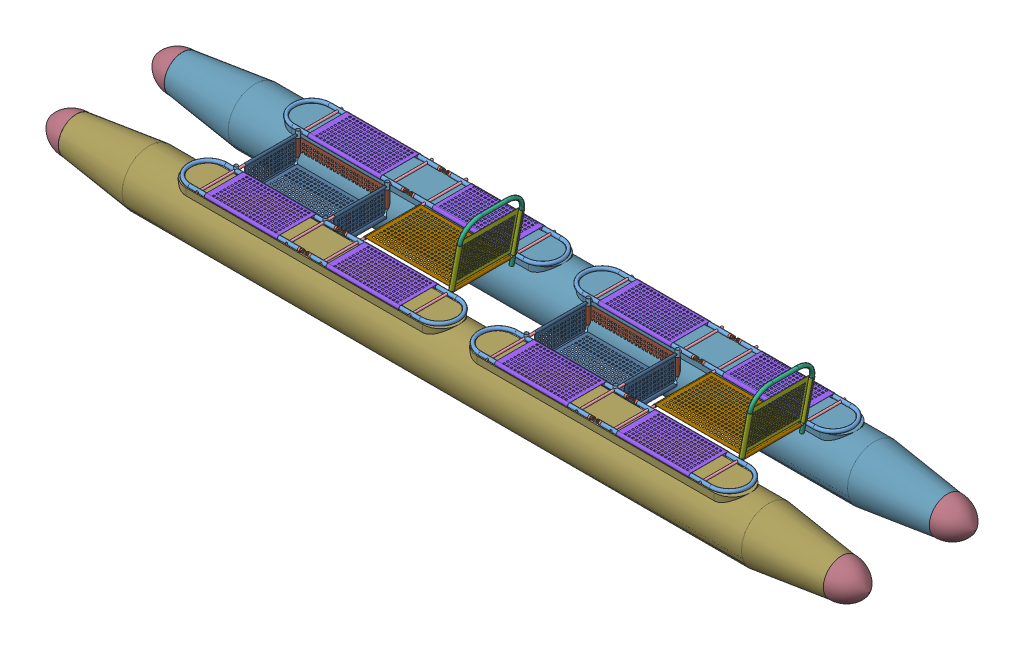
SolidWorks assembly VersionDobleV2, configuration Default. Lengths in mm.
Overall size (4504.33 666.94 886.13).
77 component instances, 14 part files, 8 mates.
Components (placement in the parent):
- FrameConTelas-1: FrameConTelas [Default] at (185.537 -150.3291 -304.6641) size (1488 506.65 807.68)
  - FrameOneSideNoAnim-1: FrameOneSideNoAnim [Default] at (577.8554 752.7862 1416.0585) size (1488 20 220)
    - F1-1: F1 [Default<As Welded>] at (120.0879 35.9229 252.3231) size (710 20 220)
    - H1-1: H1 [Default] at (120.0879 35.9229 252.3231) x (0 1 0) z (-1 0 0) size (20 20 40)
    - H2-1: H2 [Default] at (166.0879 29.9229 252.3231) x (1 0 0) z (0 1 0) size (36 12 6)
    - H1-2: H1 [Default] at (188.0879 35.9229 252.3231) x (0 1 0) z (1 0 0) size (20 20 40)
    - H2-2: H2 [Default] at (166.0879 29.9229 52.3231) x (1 0 0) z (0 1 0) size (36 12 6)
    - H1-4: H1 [Default] at (188.0879 35.9229 52.3231) x (0 1 0) z (1 0 0) size (20 20 40)
    - H1-6: H1 [Default] at (120.0879 35.9229 52.3231) x (0 1 0) z (-1 0 0) size (20 20 40)
    - F1-2: F1 [Default<As Welded>] at (188.0879 35.9229 52.3231) x (-1 0 0) z (0 0 -1) size (710 20 220)
  - FrameOneSideNoAnim-2: FrameOneSideNoAnim [Default] at (577.8554 752.7862 846.9204) size (1488 20 220)
    - F1-1: F1 [Default<As Welded>] at (120.0879 35.9229 252.3231) size (710 20 220)
    - H1-1: H1 [Default] at (120.0879 35.9229 252.3231) x (0 1 0) z (-1 0 0) size (20 20 40)
    - H2-1: H2 [Default] at (166.0879 29.9229 252.3231) x (1 0 0) z (0 1 0) size (36 12 6)
    - H1-2: H1 [Default] at (188.0879 35.9229 252.3231) x (0 1 0) z (1 0 0) size (20 20 40)
    - H2-2: H2 [Default] at (166.0879 29.9229 52.3231) x (1 0 0) z (0 1 0) size (36 12 6)
    - H1-4: H1 [Default] at (188.0879 35.9229 52.3231) x (0 1 0) z (1 0 0) size (20 20 40)
    - H1-6: H1 [Default] at (120.0879 35.9229 52.3231) x (0 1 0) z (-1 0 0) size (20 20 40)
    - F1-2: F1 [Default<As Welded>] at (188.0879 35.9229 52.3231) x (-1 0 0) z (0 0 -1) size (710 20 220)
  - F2-1: F2 [Default] at (147.9433 788.709 883.2223) x (0.974991 0.222245 0) z (0 0 1) size (12 12 800)
  - F2-2: F2 [Default] at (637.9433 788.709 877.7586) x (-0.420932 0.907092 0) z (0 0 1) size (12 12 800)
  - F2-3: F2 [Default] at (825.9433 788.709 876.0371) x (-0.580942 -0.813945 0) z (0 0 1) size (12 12 800)
  - F2-4: F2 [Default] at (1315.9433 788.709 883.7191) x (-0.357466 -0.933926 0) z (0 0 1) size (12 12 800)
  - F3-1: F3 [Default<As Welded>] at (147.9433 808.709 1464.7193) x (0 0 -1) z (1 0 0) size (400 170 20)
  - F3-2: F3 [Default<As Welded>] at (637.9433 808.709 1464.7193) x (0 0 -1) z (1 0 0) size (400 170 20)
  - F4-1: F4 [Default<As Welded>] at (1306.7067 739.5696 1111.2876) x (0 0 -1) z (0.982789 -0.184731 0) size (360 410 20)
  - T1-1: T1 [Default] at (1317.6609 797.8471 1111.2876) x (0 0 1) z (-0.982789 0.184731 0) size (363 240 23)
  - T2-1: T2 [Default] at (1270.4972 788.709 1099.2435) x (0 0 -1) z (0 1 0) size (223 400 23)
  - T2-2: T2 [Default] at (186.063 788.709 899.2435) x (0 0 1) z (0 1 0) size (223 400 23)
  - T2-3: T2 [Default] at (188.7365 788.709 1468.3816) x (0 0 1) z (0 1 0) size (223 400 23)
  - T2-4: T2 [Default] at (855.5815 788.709 1468.3816) x (0 0 1) z (0 1 0) size (223 400 23)
  - T3-1: T3 [Default] at (825.9433 788.709 1129.5821) size (505 15 310)
  - T4-1: T4 [Default] at (147.9433 648.709 1138.0439) size (512 158 280)
  - T5-1: T5 [Default] at (147.9433 684.6401 1124.7193) x (1 0 0) z (0 0 1) size (512 90 22)
  - T5-2: T5 [Default] at (637.9433 683.336 1464.7193) x (-1 0 0) z (0 0 -1) size (512 90 22)
- FrameConTelas-2: FrameConTelas [Default] at (-1407.9985 -150.3291 -304.6641) size (1488 506.65 807.68)
  - FrameOneSideNoAnim-1: FrameOneSideNoAnim [Default] at (577.8554 752.7862 1416.0585) size (1488 20 220)
    - F1-1: F1 [Default<As Welded>] at (120.0879 35.9229 252.3231) size (710 20 220)
    - H1-1: H1 [Default] at (120.0879 35.9229 252.3231) x (0 1 0) z (-1 0 0) size (20 20 40)
    - H2-1: H2 [Default] at (166.0879 29.9229 252.3231) x (1 0 0) z (0 1 0) size (36 12 6)
    - H1-2: H1 [Default] at (188.0879 35.9229 252.3231) x (0 1 0) z (1 0 0) size (20 20 40)
    - H2-2: H2 [Default] at (166.0879 29.9229 52.3231) x (1 0 0) z (0 1 0) size (36 12 6)
    - H1-4: H1 [Default] at (188.0879 35.9229 52.3231) x (0 1 0) z (1 0 0) size (20 20 40)
    - H1-6: H1 [Default] at (120.0879 35.9229 52.3231) x (0 1 0) z (-1 0 0) size (20 20 40)
    - F1-2: F1 [Default<As Welded>] at (188.0879 35.9229 52.3231) x (-1 0 0) z (0 0 -1) size (710 20 220)
  - FrameOneSideNoAnim-2: FrameOneSideNoAnim [Default] at (577.8554 752.7862 846.9204) size (1488 20 220)
    - F1-1: F1 [Default<As Welded>] at (120.0879 35.9229 252.3231) size (710 20 220)
    - H1-1: H1 [Default] at (120.0879 35.9229 252.3231) x (0 1 0) z (-1 0 0) size (20 20 40)
    - H2-1: H2 [Default] at (166.0879 29.9229 252.3231) x (1 0 0) z (0 1 0) size (36 12 6)
    - H1-2: H1 [Default] at (188.0879 35.9229 252.3231) x (0 1 0) z (1 0 0) size (20 20 40)
    - H2-2: H2 [Default] at (166.0879 29.9229 52.3231) x (1 0 0) z (0 1 0) size (36 12 6)
    - H1-4: H1 [Default] at (188.0879 35.9229 52.3231) x (0 1 0) z (1 0 0) size (20 20 40)
    - H1-6: H1 [Default] at (120.0879 35.9229 52.3231) x (0 1 0) z (-1 0 0) size (20 20 40)
    - F1-2: F1 [Default<As Welded>] at (188.0879 35.9229 52.3231) x (-1 0 0) z (0 0 -1) size (710 20 220)
  - F2-1: F2 [Default] at (147.9433 788.709 883.2223) x (0.974991 0.222245 0) z (0 0 1) size (12 12 800)
  - F2-2: F2 [Default] at (637.9433 788.709 877.7586) x (-0.420932 0.907092 0) z (0 0 1) size (12 12 800)
  - F2-3: F2 [Default] at (825.9433 788.709 876.0371) x (-0.580942 -0.813945 0) z (0 0 1) size (12 12 800)
  - F2-4: F2 [Default] at (1315.9433 788.709 883.7191) x (-0.357466 -0.933926 0) z (0 0 1) size (12 12 800)
  - F3-1: F3 [Default<As Welded>] at (147.9433 808.709 1464.7193) x (0 0 -1) z (1 0 0) size (400 170 20)
  - F3-2: F3 [Default<As Welded>] at (637.9433 808.709 1464.7193) x (0 0 -1) z (1 0 0) size (400 170 20)
  - F4-1: F4 [Default<As Welded>] at (1306.7067 739.5696 1111.2876) x (0 0 -1) z (0.982789 -0.184731 0) size (360 410 20)
  - T1-1: T1 [Default] at (1317.6609 797.8471 1111.2876) x (0 0 1) z (-0.982789 0.184731 0) size (363 240 23)
  - T2-1: T2 [Default] at (1270.4972 788.709 1099.2435) x (0 0 -1) z (0 1 0) size (223 400 23)
  - T2-2: T2 [Default] at (186.063 788.709 899.2435) x (0 0 1) z (0 1 0) size (223 400 23)
  - T2-3: T2 [Default] at (188.7365 788.709 1468.3816) x (0 0 1) z (0 1 0) size (223 400 23)
  - T2-4: T2 [Default] at (855.5815 788.709 1468.3816) x (0 0 1) z (0 1 0) size (223 400 23)
  - T3-1: T3 [Default] at (825.9433 788.709 1129.5821) size (505 15 310)
  - T4-1: T4 [Default] at (147.9433 648.709 1138.0439) size (512 158 280)
  - T5-1: T5 [Default] at (147.9433 684.6401 1124.7193) x (1 0 0) z (0 0 1) size (512 90 22)
  - T5-2: T5 [Default] at (637.9433 683.336 1464.7193) x (-1 0 0) z (0 0 -1) size (512 90 22)
- Ponton-1: Ponton [Default] at (3061.4153 -931.8418 263.4026) x (0 0 1) z (-1 0 0) size (300 300 4500)
  - P1-1: P1 [Default] at (1009.5571 1409.7476 1284.8904) size (300 300 4200)
  - P2-1: P2 [Default] at (1009.5571 1409.7476 884.8904) size (200 200 150)
  - P2-2: P2 [Default] at (1009.5571 1409.7476 5084.8904) x (-0.923728 -0.383049 0) z (0 0 -1) size (200 200 150)
- P1-R-2: P1-R [Default] at (1772.1996 477.0888 686.8298) x (0 0 1) z (-1 0 0) size (300 300 4200)
- P2-1: P2 [Default] at (2172.1996 477.0888 686.8298) x (0 0.924225 0.381849) z (-1 0 0) size (200 200 150)
- P2-2: P2 [Default] at (-2027.8004 477.0888 686.8298) x (0 -0.924225 -0.381849) z (1 0 0) size (200 200 150)
Mates (geometry in assembly coordinates):
- Coincident1: coincident anti-aligned: line of FrameConTelas-1/FrameOneSideNoAnim-1/F1-1 through (883.4803 638.38 1363.7175) axis (-1 0 0); line of FrameConTelas-2/FrameOneSideNoAnim-1/F1-2 through (-642.0552 638.38 1363.7175) axis (1 0 0)
- Coincident2: coincident anti-aligned: line of FrameConTelas-1/FrameOneSideNoAnim-2/F1-1 through (883.4803 638.38 594.5794) axis (-1 0 0); line of FrameConTelas-2/FrameOneSideNoAnim-2/F1-2 through (-642.0552 638.38 594.5794) axis (1 0 0)
- Parallel11: parallel anti-aligned: line of FrameConTelas-2/FrameOneSideNoAnim-1/F1-1 through (-710.0552 638.38 1363.7175) axis (-1 0 0); line of Ponton-1/P1-1 through (-1623.4751 477.9058 1272.9598) axis (1 0 0)
- Parallel14: parallel aligned: plane of FrameConTelas-2/T2-3 through (-819.262 649.88 1163.7175) normal (0 1 0); plane of Ponton-1/P1-1 through (-23.4751 627.9058 1272.9598) normal (0 1 0)
- Parallel15: parallel aligned: cylinder of Ponton-1/P1-1 through (-1623.4751 477.9058 1272.9598) axis (1 0 0) radius 150; cylinder of P1-R-2 through (-1627.8004 477.0888 686.8298) axis (1 0 0) radius 150
- Parallel16: parallel aligned: plane of FrameConTelas-1/T2-1 through (1056.0342 649.88 794.5794) normal (0 1 0); plane of P1-R-2 through (272.1996 627.0888 686.8298) normal (0 1 0)
- Coincident6: coincident aligned: circle of P1-R-2; circle of P2-1
- Coincident7: coincident aligned: circle of P1-R-2; circle of P2-2
